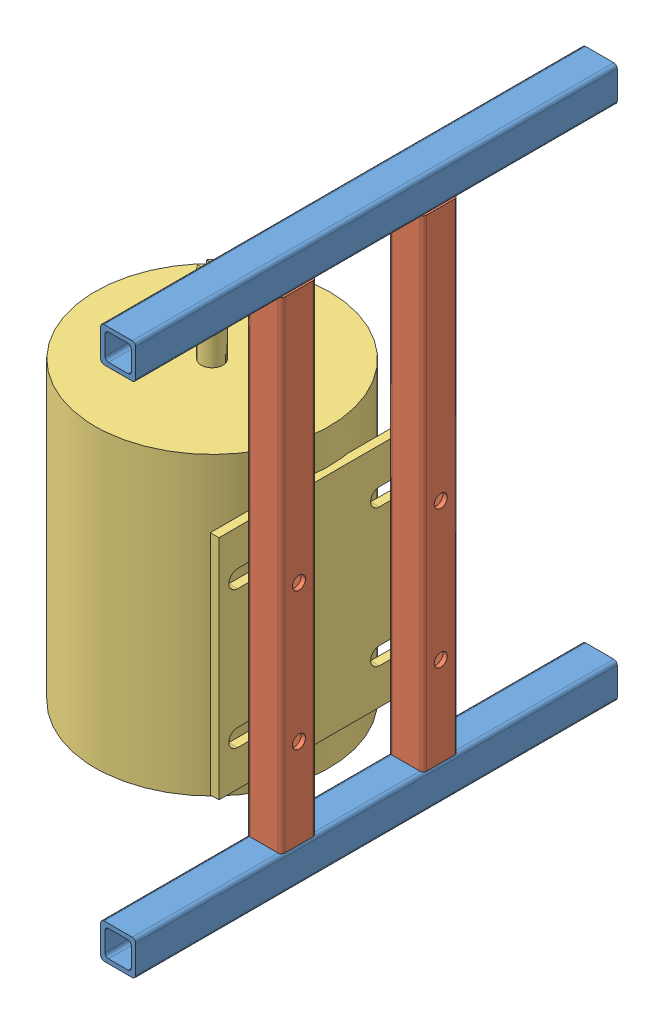
SolidWorks assembly Ensamblaje2, configuration Predeterminado. Lengths in mm.
Overall size (200.4 400.8 350).
5 component instances, 3 part files, 9 mates.
Components (placement in the parent):
- PTR - FRENTES-1: PTR - FRENTES [Predeterminado] at (57.0647 47.3332 153.2083) size (25.4 25.4 350)
- PTR - MOTOR-2: PTR - MOTOR [Predeterminado] at (57.0647 -315.3668 281.478) x (1 0 0) z (0 1 0) size (25.4 25.4 350)
- PTR - FRENTES-2: PTR - FRENTES [Predeterminado] at (57.0647 -328.0668 153.2083) size (25.4 25.4 350)
- PTR - MOTOR-3: PTR - MOTOR [Predeterminado] at (57.0647 -315.3668 384.5275) x (1 0 0) z (0 1 0) size (25.4 25.4 350)
- MotorMedia-1: MotorMedia [Predeterminado] at (-45.6353 -93.3899 332.2275) x (0 -1 0) z (0 0 -1) size (272.15 175 170)
Mates (geometry in assembly coordinates):
- Coincidente1: coincident anti-aligned: plane of PTR - FRENTES-1 through (46.8647 34.6332 503.2083) normal (0 -1 0); plane of PTR - MOTOR-2 through (67.2647 34.6332 291.678) normal (0 1 0)
- Coincidente2: coincident aligned: plane of PTR - FRENTES-1 through (44.3647 37.1332 503.2083) normal (-1 0 0); plane of PTR - MOTOR-2 through (44.3647 34.6332 291.678) normal (-1 0 0)
- Coincidente3: coincident aligned: plane of PTR - MOTOR-2 through (44.3647 34.6332 291.678) normal (-1 0 0); plane of PTR - MOTOR-3 through (44.3647 34.6332 394.7083) normal (-1 0 0)
- Coincidente4: coincident aligned: plane of PTR - MOTOR-2 through (67.2647 34.6332 291.678) normal (0 1 0); plane of PTR - MOTOR-3 through (67.2647 34.6332 394.7083) normal (0 1 0)
- Coincidente5: coincident anti-aligned: plane of PTR - MOTOR-2 through (67.2647 -315.3668 291.678) normal (0 -1 0); plane of PTR - FRENTES-2 through (46.8647 -315.3668 503.2083) normal (0 1 0)
- Coincidente6: coincident aligned: plane of PTR - FRENTES-2 through (44.3647 -338.2668 503.2083) normal (-1 0 0); plane of PTR - MOTOR-3 through (44.3647 34.6332 394.7083) normal (-1 0 0)
- Coincidente7: coincident aligned: plane of PTR - FRENTES-1 through (67.2647 37.1332 153.2083) normal (0 0 -1); plane of PTR - FRENTES-2 through (67.2647 -338.2668 153.2083) normal (0 0 -1)
- Coincidente8: coincident anti-aligned: plane of PTR - MOTOR-2 through (44.3647 34.6332 291.678) normal (-1 0 0); plane of MotorMedia-1 through (44.3647 -93.3899 332.2275) normal (1 0 0)
- Distancia1: distance = 20 mm aligned: plane of MotorMedia-1 through (38.0147 -118.3899 417.2275) normal (0 0 1); plane of PTR - MOTOR-3 through (46.8647 34.6332 397.2275) normal (0 0 1)
